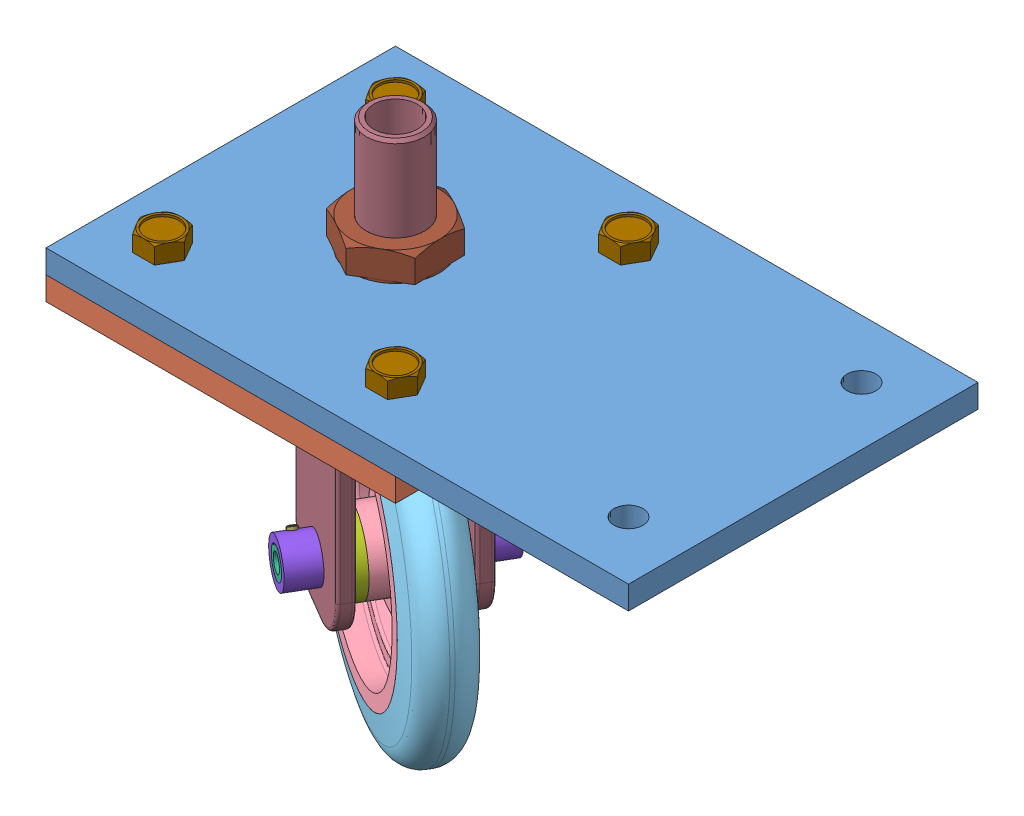
SolidWorks assembly Caster, configuration Default. Lengths in mm.
Overall size (217.83 207.67 126.12).
23 component instances, 13 part files, 27 mates.
Components (placement in the parent):
- Base.SLDPART.-1: Base.SLDPART. [Default] at (24.0932 107.2357 154.4264) size (200 8 120)
- Mount.-1: Mount. [Default] at (24.0932 99.2357 154.4264) size (120 8 120)
- Bearing-2: Bearing [Default] at (24.0932 94.2357 154.4264) x (0.99205 0 -0.125844) z (0 1 0) size (30 30 5)
- Wheel and Axle-1: Wheel and Axle [Default] at (102.4658 14.6092 168.6712) x (-0.508451 0 0.861091) z (-0.778686 -0.426894 -0.459793) size (60 110 110)
  - Wheel.-1: Wheel. [Default] at (27.5826 43.0888 61.6989) size (20 80 80)
  - Tire.-1: Tire. [Default] at (27.5826 43.0888 61.6989) size (20 110 110)
  - Axle.SLDPART-1: Axle.SLDPART [Default] at (27.5826 43.0888 61.6989) x (0 -0.083982 0.996467) z (-1 0 0) size (10 10 60)
  - Washer-1: Washer [Default] at (17.5826 43.0888 61.6989) x (0 0 1) z (-1 0 0) size (25 25 5)
  - Washer-2: Washer [Default] at (37.5826 43.0888 61.6989) x (0 -0.06397 -0.997952) z (1 0 0) size (25 25 5)
- Collar-1: Collar [Default] at (37.2694 27.2357 133.1737) x (0.745064 0.50133 0.43994) z (0.508451 0 -0.861091) size (15 15 10)
- Collar-2: Collar [Default] at (11.8469 27.2357 176.2283) x (0.745064 0.50133 0.43994) z (0.508451 0 -0.861091) size (15 15 10)
- hex screw_am-2: hex screw_am [B18.6.7M - M8 x 1.25 x 25 Indented HHMS --25N] at (-15.9068 121.2357 114.4264) x (0 -1 0) z (0 0 1) size (31 15.01 13)
- hex nut style 1_am-4: hex nut style 1_am [B18.2.4.1M - Hex nut, Style 1,  M8 x 1.25 --D-N] at (-15.9068 99.2357 114.4264) x (0.998244 0 0.059238) z (0 1 0) size (13 15.01 6.8)
- hex nut style 1_am-5: hex nut style 1_am [B18.2.4.1M - Hex nut, Style 1,  M8 x 1.25 --D-N] at (64.0932 99.2357 114.4264) x (0.998244 0 0.059238) z (0 1 0) size (13 15.01 6.8)
- hex nut style 1_am-6: hex nut style 1_am [B18.2.4.1M - Hex nut, Style 1,  M8 x 1.25 --D-N] at (-15.9068 99.2357 194.4264) x (0.998244 0 0.059238) z (0 1 0) size (13 15.01 6.8)
- hex nut style 1_am-7: hex nut style 1_am [B18.2.4.1M - Hex nut, Style 1,  M8 x 1.25 --D-N] at (64.0932 99.2357 194.4264) x (0.998244 0 0.059238) z (0 1 0) size (13 15.01 6.8)
- hex screw_am-3: hex screw_am [B18.6.7M - M8 x 1.25 x 25 Indented HHMS --25N] at (64.0932 121.2357 114.4264) x (0 -1 0) z (0 0 1) size (31 15.01 13)
- hex screw_am-4: hex screw_am [B18.6.7M - M8 x 1.25 x 25 Indented HHMS --25N] at (-15.9068 121.2357 194.4264) x (0 -1 0) z (0 0 1) size (31 15.01 13)
- hex screw_am-5: hex screw_am [B18.6.7M - M8 x 1.25 x 25 Indented HHMS --25N] at (64.0932 121.2357 194.4264) x (0 -1 0) z (0 0 1) size (31 15.01 13)
- hex nut jam_am-1: hex nut jam_am [B18.2.4.5M - Hex jam nut,  M20 x 2.5 --W-N] at (24.0932 125.2357 154.4264) x (0.999846 0 -0.017538) z (0 1 0) size (30 34.64 10)
- socket set screw flat point_am-3: socket set screw flat point_am [B18.3.6M - M3 x 0.5 x 4 Hex Socket Flat Pt. SS --N] at (33.6 34.5904 131.0071) x (0.431691 -0.865256 0.254902) z (0.70892 0.500179 0.497245) size (4 3 3)
- socket set screw flat point_am-4: socket set screw flat point_am [B18.3.6M - M3 x 0.5 x 4 Hex Socket Flat Pt. SS --N] at (8.1775 34.5904 174.0616) x (0.431691 -0.865256 0.254902) z (-0.898902 -0.389182 0.201277) size (4 3 3)
- Fork 2-1: Fork 2 [Default] at (24.0932 94.2357 154.4264) x (-0.861091 0 -0.508451) z (-0.508451 0 0.861091) size (80 207.67 80)
Mates (geometry in assembly coordinates):
- Concentric1: concentric aligned: cylinder of Base.SLDPART.-1 through (24.0932 107.2357 154.4264) axis (0 1 0) radius 12.5; cylinder of Mount.-1 through (24.0932 99.2357 154.4264) axis (0 1 0) radius 12.5
- Concentric2: concentric aligned: cylinder of Base.SLDPART.-1 through (-15.9068 107.2357 114.4264) axis (0 1 0) radius 5; cylinder of Mount.-1 through (-15.9068 99.2357 114.4264) axis (0 1 0) radius 5
- Concentric3: concentric aligned: cylinder of Base.SLDPART.-1 through (64.0932 107.2357 114.4264) axis (0 1 0) radius 5; cylinder of Mount.-1 through (64.0932 99.2357 114.4264) axis (0 1 0) radius 5
- Coincident3: coincident anti-aligned: plane of Base.SLDPART.-1 through (24.0932 107.2357 154.4264) normal (0 -1 0); plane of Mount.-1 through (24.0932 107.2357 154.4264) normal (0 1 0)
- Concentric7: concentric anti-aligned: cylinder of Mount.-1 through (24.0932 99.2357 154.4264) axis (0 1 0) radius 12.5; cylinder of Bearing-2 through (24.0932 99.2357 154.4264) axis (0 -1 0) radius 10
- Coincident5: coincident anti-aligned: plane of Mount.-1 through (24.0932 99.2357 154.4264) normal (0 -1 0); plane of Bearing-2 through (24.0932 99.2357 154.4264) normal (0 1 0)
- Concentric10: concentric aligned: cylinder of Wheel and Axle-1/Axle.SLDPART-1 through (39.8117 27.2357 128.8683) axis (-0.508451 0 0.861091) radius 5; cylinder of Collar-2 through (14.3891 27.2357 171.9228) axis (-0.508451 0 0.861091) radius 5
- Parallel2: parallel anti-aligned: plane of Wheel and Axle-1/Axle.SLDPART-1 through (14.0704 32.222 171.7346) normal (-0.431691 0.865256 -0.254902); plane of Collar-2 through (11.8469 27.2357 176.2283) normal (0.431691 -0.865256 0.254902)
- Concentric11: concentric aligned: cylinder of Wheel and Axle-1/Axle.SLDPART-1 through (39.8117 27.2357 128.8683) axis (-0.508451 0 0.861091) radius 5; cylinder of Collar-1 through (39.8117 27.2357 128.8683) axis (-0.508451 0 0.861091) radius 5
- Parallel3: parallel anti-aligned: plane of Wheel and Axle-1/Axle.SLDPART-1 through (34.4084 32.222 137.291) normal (-0.431691 0.865256 -0.254902); plane of Collar-1 through (37.2694 27.2357 133.1737) normal (0.431691 -0.865256 0.254902)
- Concentric12: concentric aligned: cylinder of Base.SLDPART.-1 through (-15.9068 107.2357 114.4264) axis (0 1 0) radius 5; cylinder of hex screw_am-2 through (-15.9068 146.6357 114.4264) axis (0 1 0) radius 4
- Coincident15: coincident anti-aligned: plane of Base.SLDPART.-1 through (24.0932 115.2357 154.4264) normal (0 1 0); plane of hex screw_am-2 through (-11.9068 115.2357 114.4264) normal (0 -1 0)
- Concentric15: concentric aligned: cylinder of hex screw_am-2 through (-15.9068 146.6357 114.4264) axis (0 1 0) radius 4; cylinder of hex nut style 1_am-4 through (-15.9068 74.1982 114.4264) axis (0 1 0) radius 4
- Coincident201: coincident anti-aligned: plane of Mount.-1 through (24.0932 99.2357 154.4264) normal (0 -1 0); plane of hex nut style 1_am-4 through (-15.4622 99.2357 106.9341) normal (0 1 0)
- Coincident221: coincident anti-aligned: plane of Wheel and Axle-1/Axle.SLDPART-1 through (34.4084 32.222 137.291) normal (-0.431691 0.865256 -0.254902); plane of socket set screw flat point_am-3 through (35.8845 31.1633 131.1973) normal (0.431691 -0.865256 0.254902)
- Concentric171: concentric anti-aligned: cylinder of Collar-1 through (34.0313 33.726 131.2617) axis (0.431691 -0.865256 0.254902) radius 1.5; cylinder of socket set screw flat point_am-3 through (28.1176 45.5791 127.7698) axis (-0.431691 0.865256 -0.254902) radius 1.5
- Coincident231: coincident anti-aligned: plane of Wheel and Axle-1/Axle.SLDPART-1 through (14.0704 32.222 171.7346) normal (-0.431691 0.865256 -0.254902); plane of socket set screw flat point_am-4 through (9.9792 31.4454 176.027) normal (0.431691 -0.865256 0.254902)
- Concentric181: concentric anti-aligned: cylinder of Collar-2 through (8.6088 33.726 174.3163) axis (0.431691 -0.865256 0.254902) radius 1.5; cylinder of socket set screw flat point_am-4 through (2.695 45.5791 170.8244) axis (-0.431691 0.865256 -0.254902) radius 1.5
- Concentric182: concentric anti-aligned: cylinder of Mount.-1 through (24.0932 99.2357 154.4264) axis (0 1 0) radius 12.5; cylinder of Fork 2-1 through (24.0932 154.2357 154.4264) axis (0 -1 0) radius 10
- Coincident232: coincident aligned: circle of Bearing-2; plane of Fork 2-1 through (24.0932 94.2357 154.4264) normal (0 1 0)
- Concentric183: concentric anti-aligned: cylinder of hex nut jam_am-1 through (24.0932 115.2357 154.4264) axis (0 1 0) radius 8.75; cylinder of Fork 2-1 through (24.0932 154.2357 154.4264) axis (0 -1 0) radius 10
- Concentric184: concentric aligned: cylinder of Wheel and Axle-1/Axle.SLDPART-1 through (39.8117 27.2357 128.8683) axis (-0.508451 0 0.861091) radius 5; cylinder of Fork 2-1 through (41.9177 27.2357 125.3015) axis (-0.508451 0 0.861091) radius 5
- Coincident233: coincident anti-aligned: plane of Wheel and Axle-1/Washer-2 through (16.9314 27.2357 167.6174) normal (-0.508451 0 0.861091); plane of Fork 2-1 through (-0.7554 11.2357 157.1738) normal (0.508451 0 -0.861091)
- Concentric185: concentric aligned: cylinder of Wheel and Axle-1/Axle.SLDPART-1 through (39.8117 27.2357 128.8683) axis (-0.508451 0 0.861091) radius 5; cylinder of Collar-2 through (14.3891 27.2357 171.9228) axis (-0.508451 0 0.861091) radius 5
- Coincident235: coincident anti-aligned: plane of Collar-2 through (14.3891 27.2357 171.9228) normal (0.508451 0 -0.861091); plane of Fork 2-1 through (-3.2977 11.2357 161.4793) normal (-0.508451 0 0.861091)
- Coincident236: coincident anti-aligned: plane of Collar-1 through (34.7272 27.2357 137.4792) normal (-0.508451 0 0.861091); plane of Fork 2-1 through (17.0403 11.2357 127.0356) normal (0.508451 0 -0.861091)
- Coincident240: coincident anti-aligned: plane of Base.SLDPART.-1 through (24.0932 115.2357 154.4264) normal (0 1 0); plane of hex nut jam_am-1 through (23.7894 115.2357 137.1086) normal (0 -1 0)
